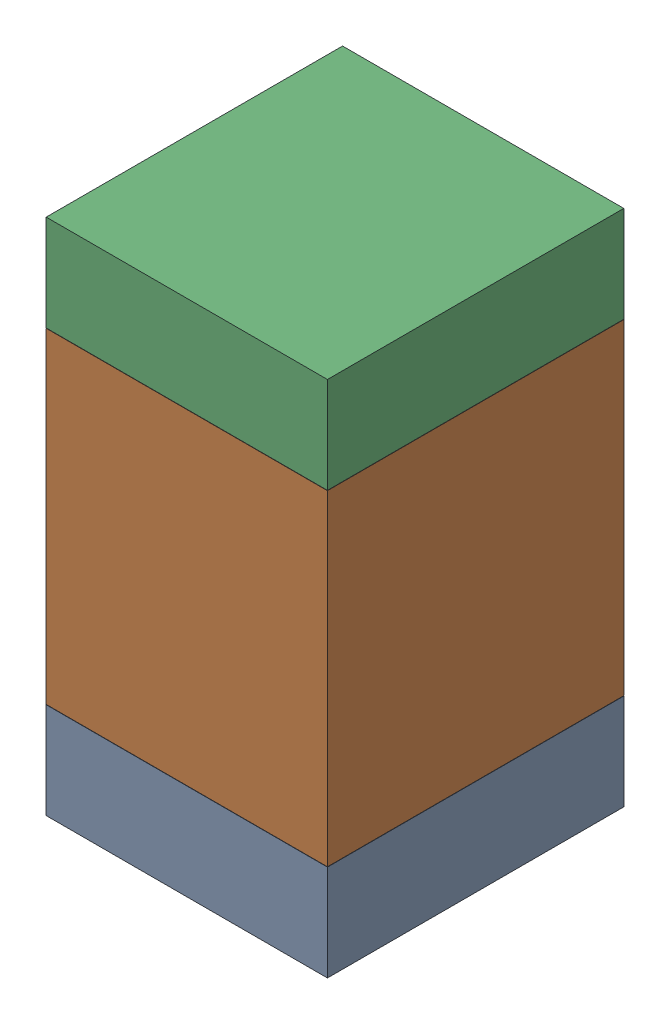
SolidWorks assembly C11, configuration Default. Lengths in mm.
Overall size (0.95 1.75 1).
6 component instances, 2 part files, 0 mates.
Components (placement in the parent):
- 6575495072-1: 6575495072 [Default] at (3.048 16.3055 0) size (0.95 0.32 1)
  - Extruded_6-1: Extruded_6 [Default] at origin size (0.95 0.32 1)
- 6575494912-1: 6575494912 [Default] at (3.048 17.018 0) size (0.95 1.1 1)
  - Extruded_7-1: Extruded_7 [Default] at origin size (0.95 1.1 1)
- 6575495072-2: 6575495072 [Default] at (3.048 17.7305 0) size (0.95 0.32 1)
  - Extruded_6-1: Extruded_6 [Default] at origin size (0.95 0.32 1)
